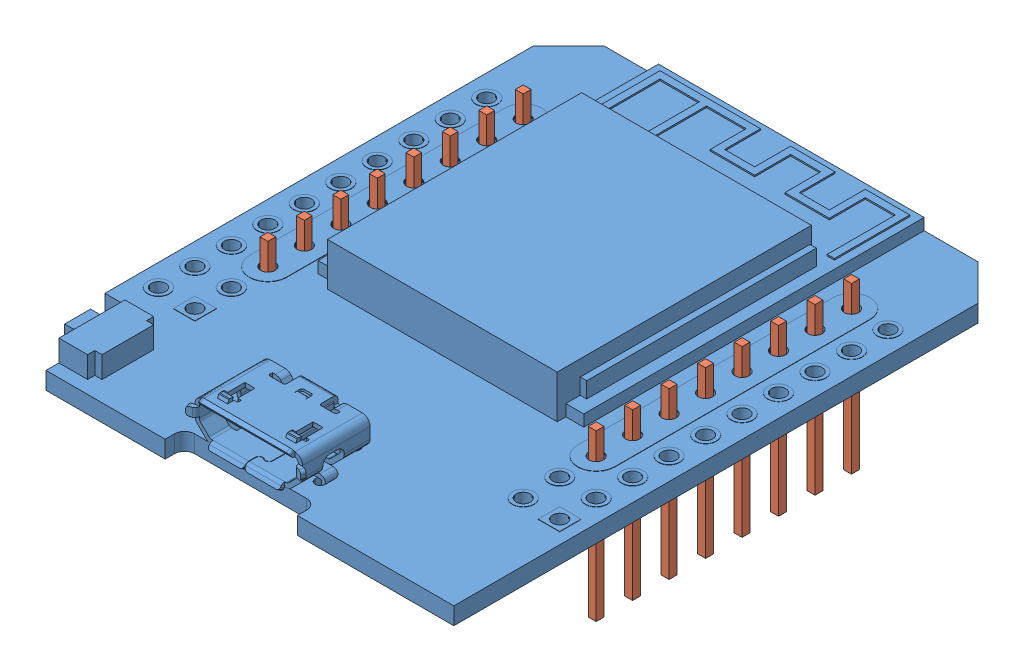
SolidWorks assembly MH-ET Live ESP32 MiniKIT - headers m, configuration Default. Lengths in mm.
Overall size (31 12.7 39).
3 component instances, 2 part files, 9 mates.
Components (placement in the parent):
- MH-ET Live ESP32 MiniKIT-1: MH-ET Live ESP32 MiniKIT [Default] at (137.257 -40.9796 -63.0415) size (31 4.22 39)
- header_m8-1: header_m8 [Default] at (11.43 -2.5 -33.03) x (0 0 1) z (-1 0 0) size (20.32 11.5 2.5)
- header_m8-2: header_m8 [Default] at (-11.43 -2.5 -33.03) x (0 0 1) z (-1 0 0) size (20.32 11.5 2.5)
Mates (geometry in assembly coordinates):
- Coincident4: coincident aligned: plane of Wemos-Mini-D1-ESP32-1 through (137.257 -40.9796 0) normal (0 0 1)
- Coincident5: coincident aligned: plane of Wemos-Mini-D1-ESP32-1 through (137.257 0 -63.0415) normal (0 1 0)
- Coincident6: coincident aligned: plane of Wemos-Mini-D1-ESP32-1 through (0 -40.9796 -63.0415) normal (1 0 0)
- Coincident7: coincident anti-aligned: plane of Wemos-Mini-D1-ESP32-1 through (-14.1 0 -5.5) normal (0 -1 0); plane of header_m8-1 through (10.18 0 -33.03) normal (0 1 0)
- Coincident8: coincident anti-aligned: plane of Wemos-Mini-D1-ESP32-1 through (-14.1 0 -5.5) normal (0 -1 0); plane of header_m8-2 through (-12.68 0 -33.03) normal (0 1 0)
- Coincident9: coincident anti-aligned: line of Wemos-Mini-D1-ESP32-1 through (11.43 -0.02 -31.76) axis (0 1 0); line of header_m8-1 through (11.43 -2.5 -31.76) axis (0 -1 0)
- Coincident10: coincident anti-aligned: line of Wemos-Mini-D1-ESP32-1 through (-11.43 -0.0395 -31.76) axis (0 1 0); line of header_m8-2 through (-11.43 -2.5 -31.76) axis (0 -1 0)
- Parallel2: parallel anti-aligned: plane of Wemos-Mini-D1-ESP32-1 through (0 -40.9796 -63.0415) normal (1 0 0); plane of header_m8-2 through (-11.43 -2.5 -33.03) normal (-1 0 0)
- Parallel3: parallel anti-aligned: plane of Wemos-Mini-D1-ESP32-1 through (0 -40.9796 -63.0415) normal (1 0 0); plane of header_m8-1 through (11.43 -2.5 -33.03) normal (-1 0 0)
